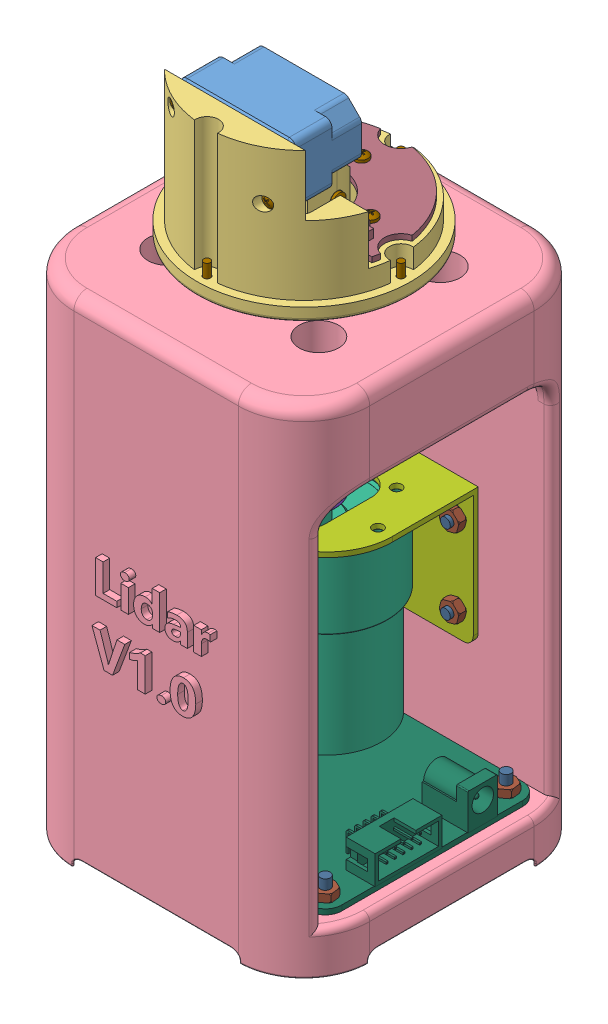
SolidWorks assembly 装配体, configuration Default. Lengths in mm.
Overall size (153.85 200.38 139.14).
41 component instances, 16 part files, 89 mates.
Components (placement in the parent):
- TFminiPlus激光测距模组-1: TFminiPlus激光测距模组 [默认] at (80.182 60.5315 66) x (-1 0 0) z (0 -1 0) size (35 21 40.5)
- 导电滑环-1: 导电滑环 [Default] at (80.182 -4.7185 45) size (53 60.9 35)
- 转子基座-1: 转子基座 [Default] at (80.182 26.2815 45) x (1 0 0) z (0 1 0) size (65 65 43.53)
- 转子盖-1: 转子盖 [Default] at (80.182 -4.7185 45) x (1 0 0) z (0 1 0) size (65 68.94 49.1) (hidden)
- 定子底座-1: 定子底座 [Default] at (80.182 -4.7185 45) x (-1 0 0) z (0 0 -1) size (90.05 152.88 92.03)
- 主轴-1: 主轴 [Default] at (80.182 45.2815 45) x (0.223653 0 -0.974669) z (-0.974669 0 -0.223653) size (8 70 8)
- MG513电机-光电编码器-1: MG513电机-光电编码器 [Default] at (80.182 -48.053 38) x (-1 0 0) z (0 0 1) size (37.69 78.06 36.8)
- 电机支架-1: 电机支架 [Default] at (80.182 -67.303 12) x (0 -1 0) z (-1 0 0) size (41.5 46 40)
- 弹性联轴器-1: 弹性联轴器 [Default] at (80.182 -41.053 45) x (-0.931269 0 -0.364332) z (0.364332 0 -0.931269) size (19 24.5 19)
- M2x6螺钉-1: M2x6螺钉 [Default] at (94.182 54.7815 70.6) x (0.634762 0.772707 0) z (-0.772707 0.634762 0) size (4 7.59 4)
- M2x6螺钉-2: M2x6螺钉 [Default] at (66.182 66.2815 70.6) x (0.634762 0.772707 0) z (-0.772707 0.634762 0) size (4 7.59 4)
- M2x6螺钉-3: M2x6螺钉 [Default] at (109.682 26.6815 45) x (0.926442 0 -0.376437) z (0.376437 0 0.926442) size (4 7.59 4)
- M2x6螺钉-4: M2x6螺钉 [Default] at (80.182 26.6815 74.5) x (0.926442 0 -0.376437) z (0.376437 0 0.926442) size (4 7.59 4)
- M2x6螺钉-5: M2x6螺钉 [Default] at (50.682 26.6815 45) x (0.926442 0 -0.376437) z (0.376437 0 0.926442) size (4 7.59 4)
- M2x6螺钉-6: M2x6螺钉 [Default] at (80.182 26.6815 15.5) x (0.926442 0 -0.376437) z (0.376437 0 0.926442) size (4 7.59 4)
- M2x6螺钉-7: M2x6螺钉 [Default] at (91.782 40.7815 45) x (0 0.994374 -0.105926) z (0 0.105926 0.994374) size (4 7.59 4)
- M2x6螺钉-8: M2x6螺钉 [Default] at (68.582 40.7815 45) x (0 -0.420997 -0.907062) z (0 -0.907062 0.420997) size (4 7.59 4)
- M3x14螺钉-1: M3x14螺钉 [Default] at (65.182 -80.053 1.3) x (-0.999764 0.021746 0) z (0.021746 0.999764 0) size (5 15.69 5)
- M3x14螺钉-2: M3x14螺钉 [Default] at (95.182 -80.053 1.3) x (-0.999764 0.021746 0) z (0.021746 0.999764 0) size (5 15.69 5)
- M3x14螺钉-3: M3x14螺钉 [Default] at (65.182 -56.053 1.3) x (-0.706437 -0.707776 0) z (-0.707776 0.706437 0) size (5 15.69 5)
- M3x14螺钉-4: M3x14螺钉 [Default] at (95.182 -56.053 1.3) x (-0.999764 0.021746 0) z (0.021746 0.999764 0) size (5 15.69 5)
- M3螺帽-1: M3螺帽 [Default] at (65.182 -56.053 15.9) x (0.704694 0.709511 0) z (-0.709511 0.704694 0) size (5.5 2.4 6.35)
- M3螺帽-2: M3螺帽 [Default] at (95.182 -56.053 15.9) x (0.704694 0.709511 0) z (-0.709511 0.704694 0) size (5.5 2.4 6.35)
- M3螺帽-3: M3螺帽 [Default] at (95.182 -80.053 15.9) x (0.704694 0.709511 0) z (-0.709511 0.704694 0) size (5.5 2.4 6.35)
- M3螺帽-4: M3螺帽 [Default] at (65.182 -80.053 15.9) x (0.704694 0.709511 0) z (-0.709511 0.704694 0) size (5.5 2.4 6.35)
- M5x8螺钉-1: M5x8螺钉 [Default] at (103.182 -9.1185 45) x (0.916823 0 0.399293) z (-0.399293 0 0.916823) size (8.4 11.15 8.4)
- M5x8螺钉-2: M5x8螺钉 [Default] at (57.182 -9.1185 45) x (0.916823 0 0.399293) z (-0.399293 0 0.916823) size (8.4 11.15 8.4)
- 转子PCB-1: 转子PCB [默认] at (80.182 36.2815 45) x (0.770885 0 0.636975) z (0 1 0) size (54.26 53.21 16.1)
- 红外接收管-1: 红外接收管 [Default] at (62.1603 9.2815 26.9784) x (-0.282622 0 -0.959231) z (0.959231 0 -0.282622) size (5.75 36.7 5.51)
- M2x6螺钉-9: M2x6螺钉 [Default] at (62.9478 39.4815 41.9612) x (0.21369 0 -0.976901) z (-0.976901 0 -0.21369) size (4 7.59 4)
- M2x6螺钉-10: M2x6螺钉 [Default] at (80.182 39.4815 27.5) x (0.182698 0 -0.983169) z (-0.983169 0 -0.182698) size (4 7.59 4)
- M2x6螺钉-11: M2x6螺钉 [Default] at (97.4161 39.4815 41.9612) x (0.21369 0 -0.976901) z (-0.976901 0 -0.21369) size (4 7.59 4)
- 定子PCB-3: 定子PCB [Default] at (79.6134 -117.553 44.4445) x (0.704694 0 0.709511) z (0 1 0) size (98.35 98.42 12.6)
- M3x14螺钉-5: M3x14螺钉 [Default] at (45.182 -126.253 73.5) x (0.547089 0 0.837075) z (-0.837075 0 0.547089) size (5 15.69 5)
- M3x14螺钉-6: M3x14螺钉 [Default] at (45.182 -126.253 18.5) x (-0.227209 0 0.973846) z (-0.973846 0 -0.227209) size (5 15.69 5)
- M3x14螺钉-7: M3x14螺钉 [Default] at (115.182 -126.253 18.5) x (-0.227209 0 0.973846) z (-0.973846 0 -0.227209) size (5 15.69 5)
- M3x14螺钉-8: M3x14螺钉 [Default] at (115.182 -126.253 73.5) x (-0.227209 0 0.973846) z (-0.973846 0 -0.227209) size (5 15.69 5)
- M3螺帽-5: M3螺帽 [Default] at (45.182 -113.553 18.5) x (0.393038 0 -0.919522) z (-0.919522 0 -0.393038) size (5.5 2.4 6.35)
- M3螺帽-6: M3螺帽 [Default] at (115.182 -113.553 73.5) x (0.393038 0 -0.919522) z (-0.919522 0 -0.393038) size (5.5 2.4 6.35)
- M3螺帽-7: M3螺帽 [Default] at (115.182 -113.553 18.5) x (0.393038 0 -0.919522) z (-0.919522 0 -0.393038) size (5.5 2.4 6.35)
- M3螺帽-8: M3螺帽 [Default] at (45.182 -113.553 73.5) x (0.393038 0 -0.919522) z (-0.919522 0 -0.393038) size (5.5 2.4 6.35)
Mates (geometry in assembly coordinates):
- 同心3: concentric: cylinder of ? through (45 20.2815 -80.182) axis (0 -1 0) radius 17.5; cylinder of ? through (45 20.2815 -80.182) axis (0 -1 0) radius 17.75
- 重合18: coincident: plane of ?; unknown of ?
- 重合19: coincident: plane of ? through (45 26.2815 -80.182) normal (0 1 0); plane of ? through (45 26.2815 -80.182) normal (0 -1 0)
- 重合20: coincident: line of ? through (66 60.5315 -80.182) axis (1 0 0); unknown of ?
- 同心5: concentric: cylinder of ? through (62 54.7815 -94.182) axis (1 0 0) radius 1; cylinder of ? through (88 54.7815 -94.182) axis (-1 0 0) radius 1.1
- 同心6: concentric: cylinder of ? through (62 66.2815 -66.182) axis (1 0 0) radius 1; cylinder of ? through (88 66.2815 -66.182) axis (-1 0 0) radius 1.1
- 平行3: parallel: unknown of ?; line of ? through (43 -4.7185 -80.182) axis (1 0 0)
- 同心7: concentric: cylinder of ? through (45 36.2815 -80.182) axis (0 -1 0) radius 30; cylinder of ? through (45 -63.6424 -80.182) axis (0 1 0) radius 30.5
- 重合25: coincident: circle of ?; plane of ? through (45 45.2815 -80.182) normal (0 1 0)
- 同心15: concentric: cylinder of ? through (45 49.2815 -80.182) axis (0 -1 0) radius 4.05; cylinder of ? through (45 -24.7185 -80.182) axis (0 1 0) radius 4
- 同心16: concentric: cylinder of ? through (45 -20.7185 -80.182) axis (0 1 0) radius 4; cylinder of ? through (45 -24.7185 -80.182) axis (0 1 0) radius 4
- 重合44: coincident: plane of ? through (38 -48.053 -80.182) normal (0 1 0); plane of ? through (58 -48.053 -100.182) normal (0 -1 0)
- 同心23: concentric: cylinder of ? through (51.4234 -54.053 -87.932) axis (0 1 0) radius 1.5; cylinder of ? through (51.4234 -46.553 -87.932) axis (0 -1 0) radius 1.6
- 同心24: concentric: cylinder of ? through (38 -54.053 -64.682) axis (0 1 0) radius 1.5; cylinder of ? through (38 -46.553 -64.682) axis (0 -1 0) radius 1.6
- 同心25: concentric: cylinder of ? through (45 -28.253 -80.182) axis (0 -1 0) radius 3; cylinder of ? through (45 -25.053 -80.182) axis (0 -1 0) radius 3
- 距离5: distance = 1 mm: plane of assembly; plane of assembly; plane of 弹性联轴器-1 through (80.182 -41.053 45) normal (0 -1 0); plane of MG513电机-光电编码器-1 through (80.182 -42.053 45) normal (0 1 0)
- 重合47: coincident: plane of ? through (45 20.2815 -80.182) normal (0 1 0); plane of ? through (45 20.2815 -80.182) normal (0 1 0)
- 同心26: concentric: cylinder of ? through (45 -24.7185 -80.182) axis (0 1 0) radius 4; cylinder of ? through (45 -32.553 -80.182) axis (0 1 0) radius 4
- 平行4: parallel: unknown of ?; unknown of ?
- 重合48: coincident: plane of ? through (45 30.2815 -80.182) normal (0 1 0); plane of ? through (45 30.2815 -80.182) normal (0 -1 0)
- 同心27: concentric: cylinder of ? through (88 54.7815 -94.182) axis (-1 0 0) radius 1.1; cylinder of ? through (63 54.7815 -94.182) axis (1 0 0) radius 1
- 重合49: coincident: line of ? through (69 115.565 -58.7577) axis (1 0 0); unknown of ?
- 同心28: concentric: cylinder of ? through (88 66.2815 -66.182) axis (-1 0 0) radius 1.1; cylinder of ? through (63 66.2815 -66.182) axis (1 0 0) radius 1
- 重合50: coincident: line of ? through (69 115.565 -58.7577) axis (1 0 0); unknown of ?
- 同心29: concentric: cylinder of ? through (45 36.2815 -109.682) axis (0 -1 0) radius 1.1; cylinder of ? through (45 34.2815 -109.682) axis (0 -1 0) radius 1
- 重合51: coincident: plane of ? through (45 28.2815 -80.182) normal (0 -1 0); plane of ? through (45 28.2815 -109.682) normal (0 1 0)
- 同心30: concentric: cylinder of ? through (15.5 36.2815 -80.182) axis (0 -1 0) radius 1.1; cylinder of ? through (15.5 34.2815 -80.182) axis (0 -1 0) radius 1
- 重合52: coincident: plane of ? through (45 28.2815 -80.182) normal (0 -1 0); plane of ? through (15.5 28.2815 -80.182) normal (0 1 0)
- 同心31: concentric: cylinder of ? through (74.5 36.2815 -80.182) axis (0 -1 0) radius 1.1; cylinder of ? through (74.5 34.2815 -80.182) axis (0 -1 0) radius 1
- 重合53: coincident: plane of ? through (45 28.2815 -80.182) normal (0 -1 0); plane of ? through (74.5 28.2815 -80.182) normal (0 1 0)
- 同心32: concentric: cylinder of ? through (45 36.2815 -50.682) axis (0 -1 0) radius 1.1; cylinder of ? through (45 34.2815 -50.682) axis (0 -1 0) radius 1
- 重合54: coincident: plane of ? through (45 28.2815 -80.182) normal (0 -1 0); plane of ? through (45 28.2815 -50.682) normal (0 1 0)
- 同心33: concentric: cylinder of ? through (45 40.7815 -95.182) axis (0 0 1) radius 0.95; cylinder of ? through (45 40.7815 -76.182) axis (0 0 1) radius 1
- 重合55: coincident: unknown of ?; unknown of ?
- 同心34: concentric: cylinder of ? through (45 40.7815 -95.182) axis (0 0 1) radius 0.95; cylinder of ? through (45 40.7815 -84.182) axis (0 0 -1) radius 1
- 重合56: coincident: unknown of ?; unknown of ?
- 同心35: concentric: cylinder of ? through (18 -80.053 -65.182) axis (-1 0 0) radius 1.5; cylinder of ? through (17 -80.053 -65.182) axis (-1 0 0) radius 1.5
- 重合57: coincident: unknown of ?; line of ? through (3 -80.053 -65.182) axis (1 0 0)
- 重合59: coincident: unknown of ?; line of ? through (3 -56.053 -65.182) axis (1 0 0)
- 同心37: concentric: cylinder of ? through (18 -56.053 -95.182) axis (-1 0 0) radius 1.5; cylinder of ? through (17 -56.053 -95.182) axis (-1 0 0) radius 1.5
- 重合60: coincident: unknown of ?; line of ? through (3 -56.053 -95.182) axis (1 0 0)
- 同心38: concentric: cylinder of ? through (18 -80.053 -95.182) axis (-1 0 0) radius 1.5; cylinder of ? through (17 -80.053 -95.182) axis (-1 0 0) radius 1.5
- 重合61: coincident: unknown of ?; line of ? through (3 -80.053 -95.182) axis (1 0 0)
- 同心39: concentric: cylinder of ? through (17 -56.053 -65.182) axis (-1 0 0) radius 1.5; cylinder of ? through (13.5 -56.053 -65.182) axis (1 0 0) radius 1.5
- 重合62: coincident: line of ? through (13.5 -67.303 -80.182) axis (1 0 0); unknown of ?
- 同心40: concentric: cylinder of ? through (17 -56.053 -95.182) axis (-1 0 0) radius 1.5; cylinder of ? through (13.5 -56.053 -95.182) axis (1 0 0) radius 1.5
- 重合63: coincident: line of ? through (13.5 -67.303 -80.182) axis (1 0 0); unknown of ?
- 同心41: concentric: cylinder of ? through (17 -80.053 -95.182) axis (-1 0 0) radius 1.5; cylinder of ? through (13.5 -80.053 -95.182) axis (1 0 0) radius 1.5
- 重合64: coincident: line of ? through (13.5 -67.303 -80.182) axis (1 0 0); unknown of ?
- 同心42: concentric: cylinder of ? through (17 -80.053 -65.182) axis (-1 0 0) radius 1.5; cylinder of ? through (13.5 -80.053 -65.182) axis (1 0 0) radius 1.5
- 重合65: coincident: line of ? through (13.5 -67.303 -80.182) axis (1 0 0); unknown of ?
- 同心43: concentric: cylinder of ? through (45 5.2815 -103.182) axis (0 -1 0) radius 2.8; cylinder of ? through (45 1.7815 -103.182) axis (0 -1 0) radius 2.5
- 重合66: coincident: plane of ? through (45 -6.2185 -101.682) normal (0 -1 0); plane of ? through (45 -6.2185 -103.182) normal (0 1 0)
- 同心44: concentric: cylinder of ? through (45 5.2815 -57.182) axis (0 -1 0) radius 2.8; cylinder of ? through (45 1.7815 -57.182) axis (0 -1 0) radius 2.5
- 重合67: coincident: plane of ? through (45 -6.2185 -58.682) normal (0 -1 0); plane of ? through (45 -6.2185 -57.182) normal (0 1 0)
- 同心45: concentric: cylinder of ? through (15.5 20.382 -80.182) axis (0 1 0) radius 3.5; cylinder of ? through (15.5 37.8815 -80.182) axis (0 -1 0) radius 5
- 同心46: concentric: cylinder of ? through (45 20.382 -50.682) axis (0 1 0) radius 3.5; cylinder of ? through (45 37.8815 -50.682) axis (0 -1 0) radius 5
- 重合68: coincident: plane of ? through (45 36.2815 -80.182) normal (0 1 0); plane of ? through (45 36.2815 -80.182) normal (0 -1 0)
- 平行5: parallel: unknown of ?; unknown of ?
- 同心47: concentric: cylinder of ? through (26.9784 18.2815 -62.1603) axis (0 -1 0) radius 2.5; cylinder of ? through (26.9784 17.8815 -62.1603) axis (0 -1 0) radius 2.46
- 重合69: coincident: plane of ? through (45 10.2815 -80.182) normal (0 -1 0); plane of ? through (26.9784 10.2815 -62.1603) normal (0 1 0)
- 同心48: concentric: cylinder of ? through (41.9612 35.4815 -97.4161) axis (0 1 0) radius 1.15; cylinder of ? through (41.9612 31.8815 -97.4161) axis (0 1 0) radius 1
- 重合70: coincident: plane of ? through (45 37.8815 -80.182) normal (0 1 0); plane of ? through (41.9612 37.8815 -97.4161) normal (0 -1 0)
- 同心49: concentric: cylinder of ? through (27.5 35.4815 -80.182) axis (0 1 0) radius 1.15; cylinder of ? through (27.5 31.8815 -80.182) axis (0 1 0) radius 1
- 重合71: coincident: plane of ? through (45 37.8815 -80.182) normal (0 1 0); plane of ? through (27.5 37.8815 -80.182) normal (0 -1 0)
- 同心50: concentric: cylinder of ? through (41.9612 35.4815 -62.9478) axis (0 1 0) radius 1.15; cylinder of ? through (41.9612 31.8815 -62.9478) axis (0 1 0) radius 1
- 重合72: coincident: plane of ? through (45 37.8815 -80.182) normal (0 1 0); plane of ? through (41.9612 37.8815 -62.9478) normal (0 -1 0)
- 重合74: coincident: plane of ? through (45 -117.553 -80.182) normal (0 1 0); plane of ? through (73.5 -117.553 -45.182) normal (0 -1 0)
- 同心53: concentric: cylinder of ? through (18.5 -107.553 -115.182) axis (0 1 0) radius 1.55; cylinder of ? through (18.5 -117.553 -115.182) axis (0 1 0) radius 1.55
- 同心54: concentric: cylinder of ? through (73.5 -107.553 -45.182) axis (0 1 0) radius 1.55; cylinder of ? through (73.5 -117.553 -45.182) axis (0 1 0) radius 1.55
- 同心55: concentric: cylinder of ? through (73.5 -107.553 -45.182) axis (0 -1 0) radius 1.55; cylinder of ? through (73.5 -110.553 -45.182) axis (0 -1 0) radius 1.5
- 重合75: coincident: plane of ? through (45 -124.553 -80.182) normal (0 -1 0); plane of ? through (73.5 -124.553 -45.182) normal (0 1 0)
- 同心56: concentric: cylinder of ? through (18.5 -107.553 -45.182) axis (0 -1 0) radius 1.55; cylinder of ? through (18.5 -110.553 -45.182) axis (0 -1 0) radius 1.5
- 重合76: coincident: plane of ? through (45 -124.553 -80.182) normal (0 -1 0); plane of ? through (18.5 -124.553 -45.182) normal (0 1 0)
- 同心57: concentric: cylinder of ? through (18.5 -107.553 -115.182) axis (0 -1 0) radius 1.55; cylinder of ? through (18.5 -110.553 -115.182) axis (0 -1 0) radius 1.5
- 重合77: coincident: plane of ? through (45 -124.553 -80.182) normal (0 -1 0); plane of ? through (18.5 -124.553 -115.182) normal (0 1 0)
- 同心58: concentric: cylinder of ? through (73.5 -107.553 -115.182) axis (0 -1 0) radius 1.55; cylinder of ? through (73.5 -110.553 -115.182) axis (0 -1 0) radius 1.5
- 重合78: coincident: plane of ? through (45 -124.553 -80.182) normal (0 -1 0); plane of ? through (73.5 -124.553 -115.182) normal (0 1 0)
- 同心60: concentric: cylinder of ? through (18.5 -110.553 -45.182) axis (0 -1 0) radius 1.5; cylinder of ? through (18.5 -115.953 -45.182) axis (0 1 0) radius 1.5
- 重合79: coincident: plane of ? through (73.5 -115.953 -45.182) normal (0 1 0); plane of ? through (18.5 -115.953 -45.182) normal (0 -1 0)
- 同心61: concentric: cylinder of ? through (73.5 -110.553 -45.182) axis (0 -1 0) radius 1.5; cylinder of ? through (73.5 -115.953 -45.182) axis (0 1 0) radius 1.5
- 重合80: coincident: plane of ? through (73.5 -115.953 -45.182) normal (0 1 0); plane of ? through (73.5 -115.953 -45.182) normal (0 -1 0)
- 同心62: concentric: cylinder of ? through (73.5 -110.553 -115.182) axis (0 -1 0) radius 1.5; cylinder of ? through (73.5 -115.953 -115.182) axis (0 1 0) radius 1.5
- 同心63: concentric: cylinder of ? through (18.5 -110.553 -115.182) axis (0 -1 0) radius 1.5; cylinder of ? through (18.5 -115.953 -115.182) axis (0 1 0) radius 1.5
- 重合81: coincident: plane of ? through (73.5 -115.953 -45.182) normal (0 1 0); plane of ? through (18.5 -115.953 -115.182) normal (0 -1 0)
- 重合82: coincident: plane of ? through (73.5 -115.953 -45.182) normal (0 1 0); plane of ? through (73.5 -115.953 -115.182) normal (0 -1 0)
- 同心64: concentric: cylinder of ? through (18 -56.053 -65.182) axis (-1 0 0) radius 1.5; cylinder of ? through (17 -56.053 -65.182) axis (-1 0 0) radius 1.5
- 同心65: concentric: cylinder of ? through (12 -56.053 -65.182) axis (1 0 0) radius 1.75; cylinder of ? through (17 -56.053 -65.182) axis (-1 0 0) radius 1.5
- 重合84: coincident: plane of assembly; plane of 定子底座-1 through (125.182 20.2815 0) normal (0 0 -1); plane of assembly
